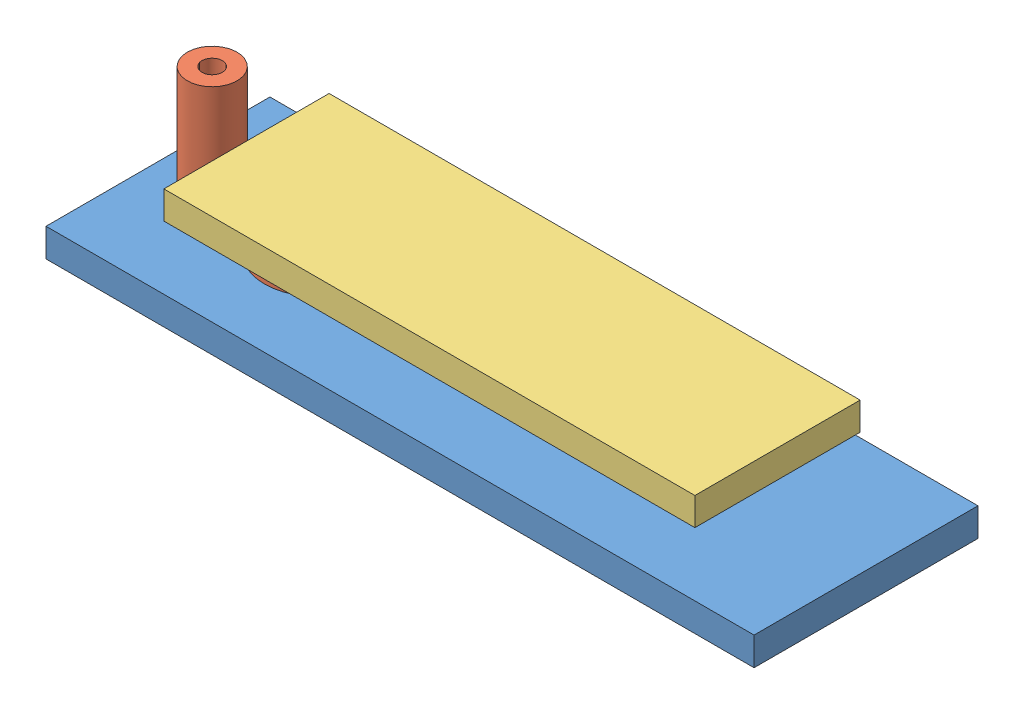
SolidWorks assembly ContactAluFer, configuration Default. Lengths in mm.
Overall size (80 15.57 25.3).
3 component instances, 3 part files, 5 mates.
Components (placement in the parent):
- Contact_barreAlu-1: Contact_barreAlu [Default] at (-13.9029 35.8024 53.6961) size (80 3.2 25.3)
- ConnecteurAAnneau-1: ConnecteurAAnneau [Default] at (4.0971 39.0024 66.3461) x (0 0 1) z (-1 0 0) size (11.92 12.37 20.64)
- Contact_barreFer-1: Contact_barreFer [Default] at (-3.9029 42.8524 75.6811) size (60 3.15 18.67)
Mates (geometry in assembly coordinates):
- Parallel6: parallel anti-aligned: line of Contact_barreFer-1 through (56.0971 42.8524 66.3461) axis (-1 0 0)
- Coincident8: coincident anti-aligned: plane of Contact_barreAlu-1 through (-13.9029 39.0024 53.6961) normal (0 1 0); plane of ConnecteurAAnneau-1 through (4.0971 39.0024 66.3461) normal (0 -1 0)
- Coincident9: coincident aligned: line of ConnecteurAAnneau-1 through (-7.7779 39.0024 66.3461) axis (1 0 0)
- Coincident12: coincident: point of ConnecteurAAnneau-1
- Distance1: distance = 3.85 mm anti-aligned: plane of Contact_barreFer-1 through (-3.9029 42.8524 75.6811) normal (0 -1 0); plane of Contact_barreAlu-1 through (-13.9029 39.0024 53.6961) normal (0 1 0)
